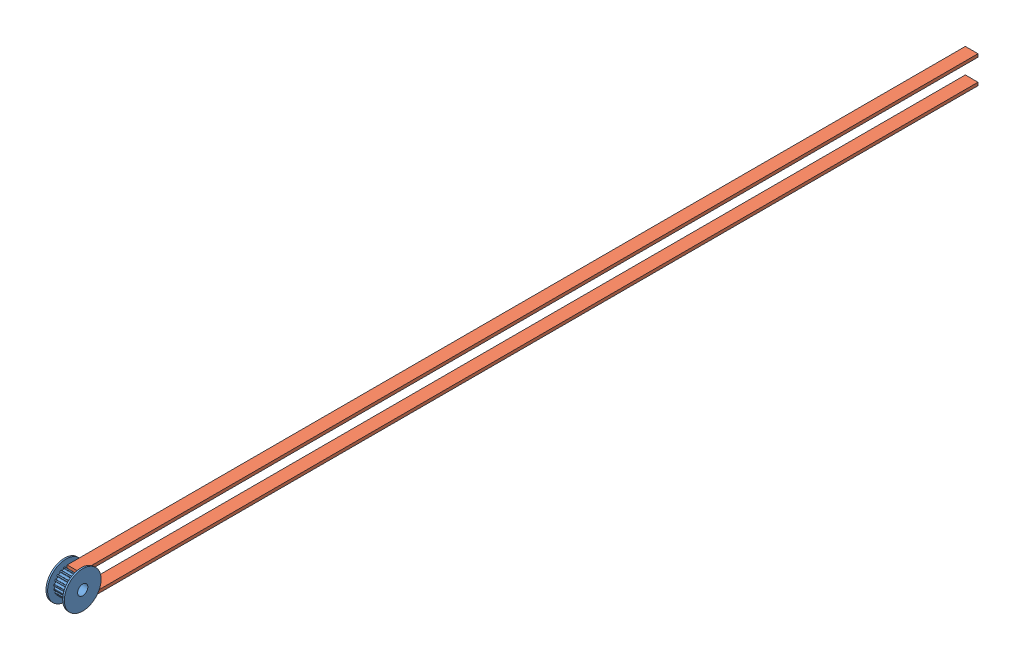
SolidWorks assembly Poleas, configuration Default. Lengths in mm.
Overall size (9 18 449).
3 component instances, 2 part files, 6 mates.
Components (placement in the parent):
- GT2_20t_wheel_pulley 5mm bore-1: GT2_20t_wheel_pulley 5mm bore [Конфигурация1] at (-6.5711 9.8872 9.0944) x (1 0 0) z (0 -1 0) size (9 18 18)
- Gt2-450mm-1: Gt2-450mm [Predeterminado] at (-5.1711 15.1872 9.0944) size (6.2 1.5 440)
- Gt2-450mm-2: Gt2-450mm [Predeterminado] at (-5.1711 3.0872 9.0944) size (6.2 1.5 440)
Mates (geometry in assembly coordinates):
- Distancia2: distance = 0.6 mm anti-aligned: plane of Gt2-450mm-2 through (-5.1711 4.5872 9.0944) normal (-1 0 0); plane of GT2_20t_wheel_pulley 5mm bore-1 through (-5.7711 9.8872 9.0944) normal (1 0 0)
- Paralelo1: parallel anti-aligned: plane of Gt2-450mm-1 through (-5.1711 15.1872 9.0944) normal (0 -1 0); plane of Gt2-450mm-2 through (-5.1711 4.3872 9.0944) normal (0 1 0)
- Distancia3: distance = 5.3 mm: plane of Gt2-450mm-2 through (-5.1711 4.5872 9.0944) normal (0 1 0); line of GT2_20t_wheel_pulley 5mm bore-1 through (-6.5711 9.8872 0.0944) axis (0 0 1)
- Distancia4: distance = 0 mm: plane of Gt2-450mm-2 through (-5.1711 4.5872 9.0944) normal (0 0 1); point of GT2_20t_wheel_pulley 5mm bore-1
- Distancia5: distance = 5.3 mm: plane of Gt2-450mm-1 through (-5.1711 15.1872 9.0944) normal (0 -1 0); line of GT2_20t_wheel_pulley 5mm bore-1 through (-6.5711 9.8872 0.0944) axis (0 0 1)
- Coincidente1: coincident aligned: plane of Gt2-450mm-1 through (-5.1711 16.6872 9.0944) normal (0 0 1); plane of Gt2-450mm-2 through (-5.1711 4.3872 9.0944) normal (0 0 1)
